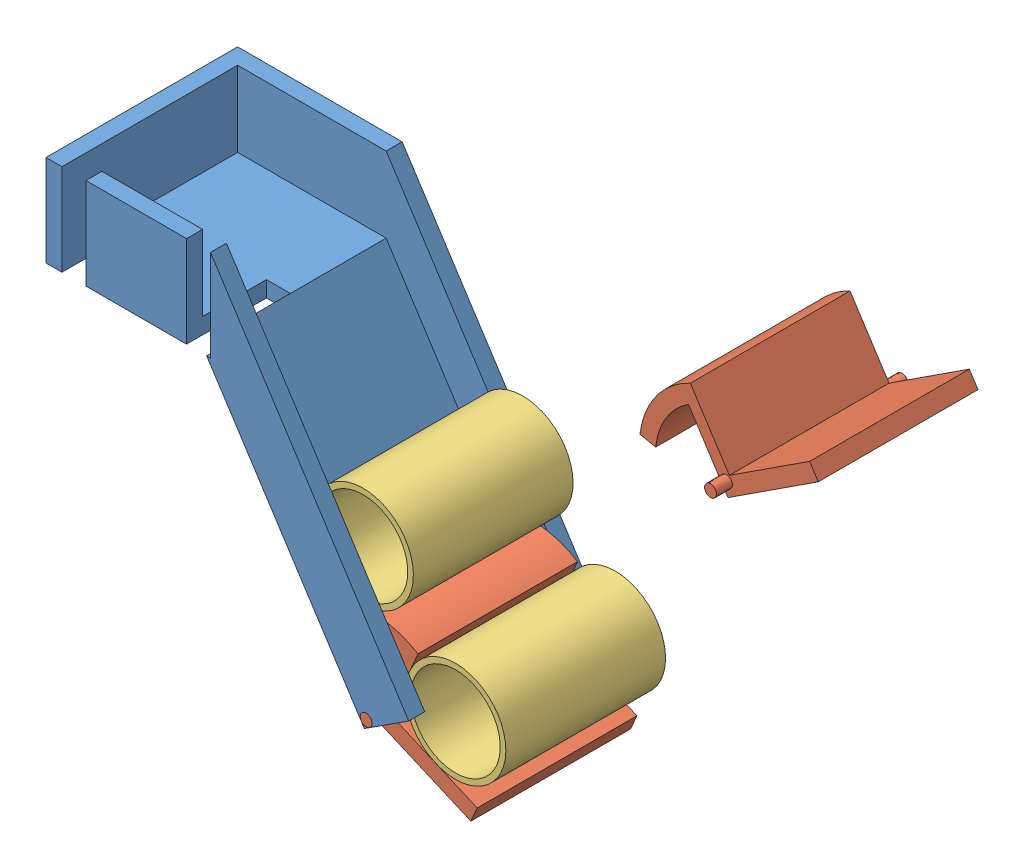
SolidWorks assembly Assemblage_Stock_Cylindre, configuration Défaut. Lengths in mm.
Overall size (351.3 237.12 242.43).
5 component instances, 3 part files, 7 mates.
Components (placement in the parent):
- Stock_Cylindre-1: Stock_Cylindre [Défaut] at (-40.7418 -39.0978 227.1534) size (227.15 210.02 120)
- Bascule-1: Bascule [Défaut] at (30.2772 -90.014 217.1534) x (0 0 -1) z (-0.399761 -0.916619 0) size (120 110.07 55.53)
- Cylindre-4: Cylindre [Défaut] at (69.1815 -79.7024 217.1534) x (0.294725 0.955582 0) z (-0.955582 0.294725 0) size (63 100 63)
- Cylindre-5: Cylindre [Défaut] at (11.2672 -13.6776 217.1534) x (0.984994 0.172588 0) z (-0.172588 0.984994 0) size (63 100 63)
- Bascule-4: Bascule [Défaut] at (114.5786 22.5157 94.7246) x (0 0 -1) z (0.542913 -0.839789 0) size (120 110.07 55.53)
Mates (geometry in assembly coordinates):
- Coaxiale2: concentric aligned: cylinder of Stock_Cylindre-1 through (23.2005 -96.9116 107.1534) axis (0 0 1) radius 3.73; cylinder of Bascule-1 through (23.2005 -96.9116 107.1534) axis (0 0 1) radius 3.73
- Coïncidente4: coincident anti-aligned: plane of Stock_Cylindre-1 through (-74.2731 107.8673 217.1534) normal (0 0 -1); plane of Bascule-1 through (16.7944 -102.2697 217.1534) normal (0 0 1)
- Tangent1: tangent anti-aligned: plane of Bascule-1 through (27.6742 -96.0782 117.1534) normal (0.916619 -0.399761 0); cylinder of Cylindre-4 through (69.1815 -79.7024 117.1534) axis (0 0 1) radius 31.5
- Coïncidente5: coincident anti-aligned: plane of Stock_Cylindre-1 through (-167.2731 107.8673 117.1534) normal (0 0 1); circle of Cylindre-4
- Tangent2: tangent anti-aligned: plane of Bascule-1 through (82.7499 -119.8837 117.1534) normal (0.396756 0.917924 0); cylinder of Cylindre-4 through (69.1815 -79.7024 117.1534) axis (0 0 1) radius 31.5
- Tangent3: tangent anti-aligned: plane of Stock_Cylindre-1 through (-74.2731 60.6173 107.1534) normal (0.839789 0.542913 0); cylinder of Cylindre-5 through (11.2672 -13.6776 117.1534) axis (0 0 1) radius 31.5
- Coïncidente9: coincident anti-aligned: plane of Stock_Cylindre-1 through (-74.2731 107.8673 217.1534) normal (0 0 -1); plane of Cylindre-5 through (11.2672 -13.6776 217.1534) normal (0 0 1)
